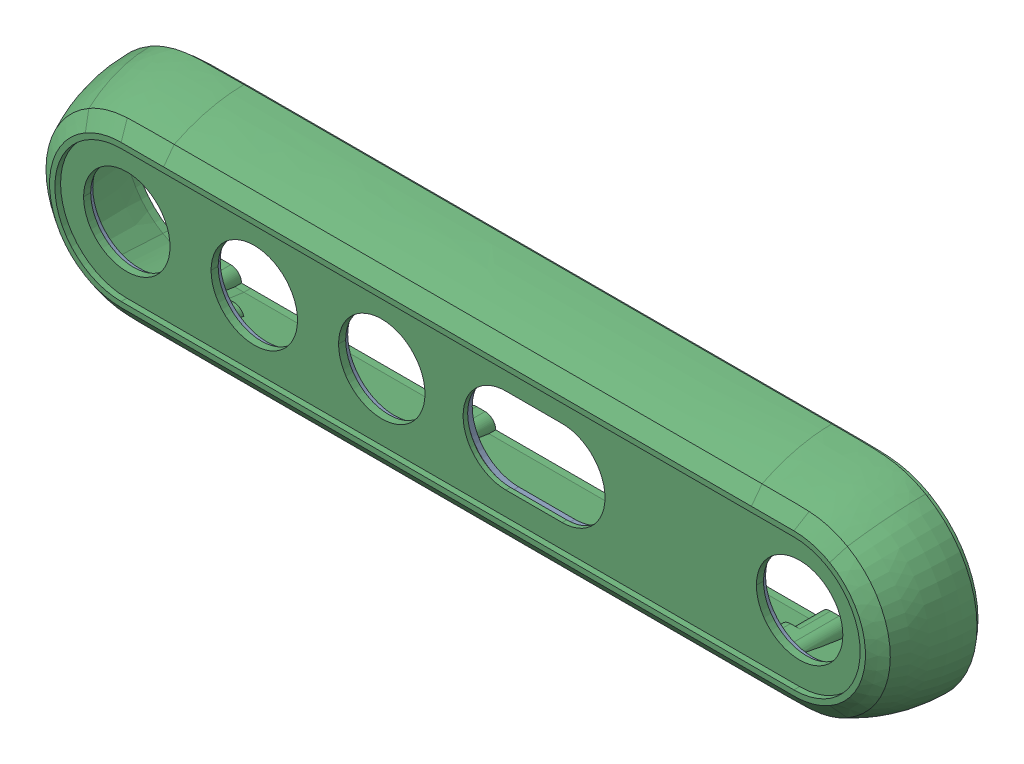
SolidWorks assembly AM0600131_ASM_2_ASM, configuration AM0600131_ASM_2_ASM. Lengths in mm.
Overall size (124 29.01 12.31).
4 component instances, 3 part files, 0 mates.
Components (placement in the parent):
- MEC060312_ASM_4_ASM-1: MEC060312_ASM_4_ASM [MEC060312_ASM_4_ASM] at origin size (111.1 18.8 0.79)
  - DS5_0390_FOAM_FRONT_D455_3-1: DS5_0390_FOAM_FRONT_D455_3 [DS5_0390_FOAM_FRONT_D455_3] at origin size (111.1 18.8 0.76)
  - DS5_0390_ADHESIVE_D455_2-1: DS5_0390_ADHESIVE_D455_2 [DS5_0390_ADHESIVE_D455_2] at (0 0 -1.32) size (111.1 18.8 0.03)
- MEC060311_6-1: MEC060311_6 [MEC060311_6] at origin size (124 29.01 12.31)
